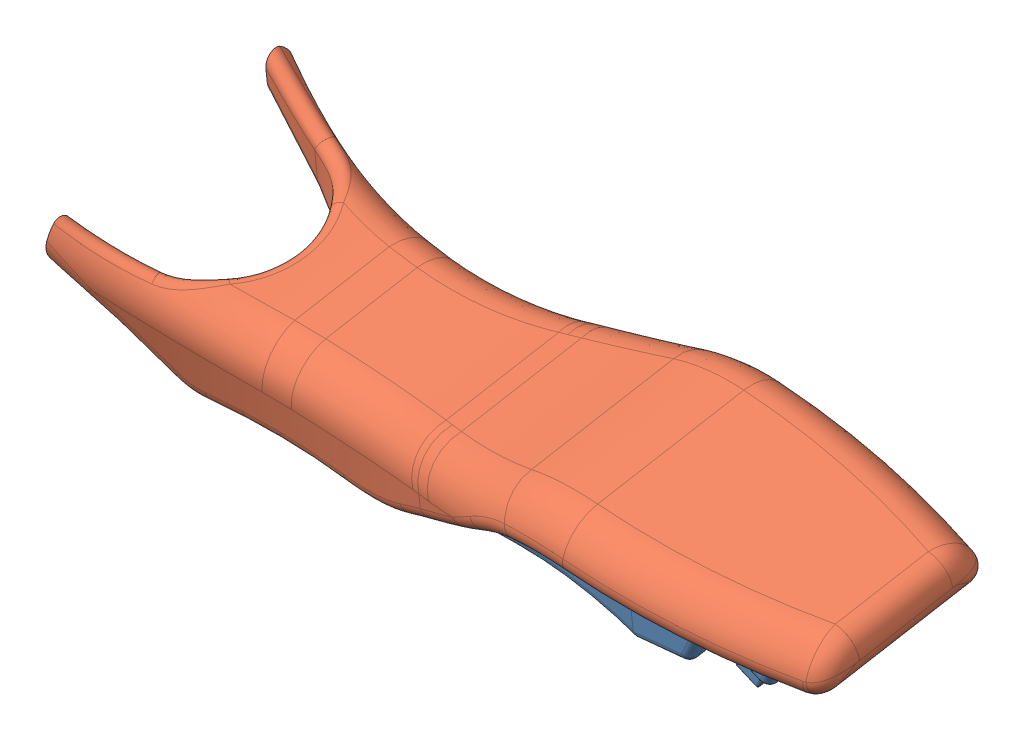
SolidWorks assembly Assem1, configuration Default. Lengths in mm.
Overall size (846.23 296.47 339.75).
2 component instances, 2 part files, 3 mates.
Components (placement in the parent):
- seat  lower-1: seat  lower [Default] at (432.9562 13.5364 440.3224) x (0.996291 -0.085691 -0.007843) z (0.007843 0.181202 -0.983415) size (581.93 113.92 186.65)
- seat2-1: seat2 [Default] at (693.0895 -48.18 159.8225) x (0.996291 -0.085691 -0.007843) z (-0.007843 -0.181202 0.983415) size (832.08 173.06 306.95)
Mates (geometry in assembly coordinates):
- Coincident6: coincident: point of assembly; point of assembly; moEndPointRef_w of seat  lower-1; moEndPointRef_w of seat2-1
- Parallel5: parallel: plane of seat  lower-1 through (452.3752 57.9983 300.6853) normal (0.085691 0.979706 0.181202); plane of seat2-1 through (701.4635 35.2827 311.6615) normal (-0.085691 -0.979706 -0.181202)
- Parallel6: parallel anti-aligned: line of seat  lower-1 through (748.0524 16.8405 383.387) axis (-0.007843 -0.181202 0.983415); line of seat2-1 through (842.0201 13.6859 499.9274) axis (0.007843 0.181202 -0.983415)
